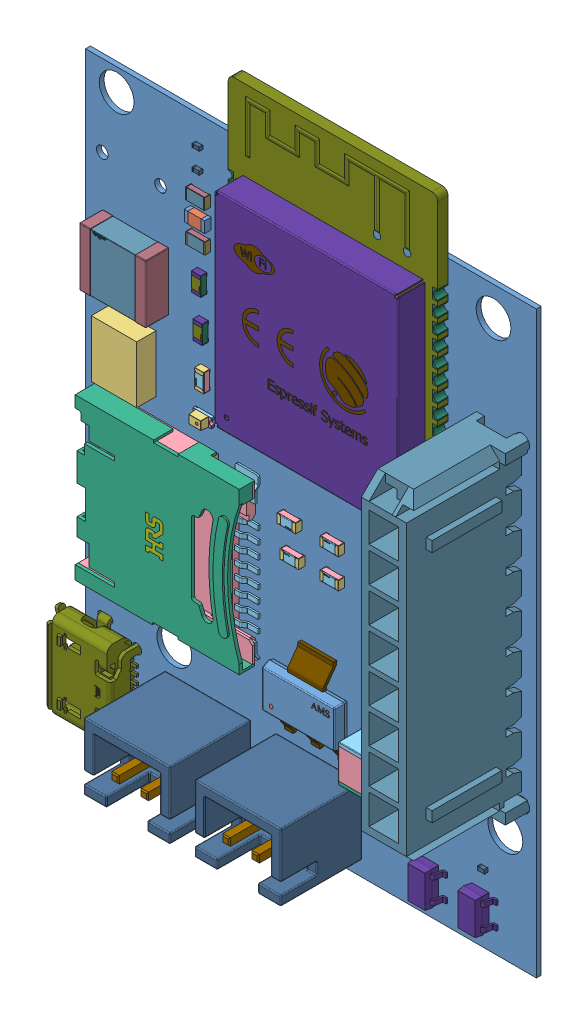
SolidWorks assembly PCB1.step, configuration Default. Lengths in mm.
Overall size (39.59 54.93 13.33).
223 component instances, 63 part files, 0 mates.
Components (placement in the parent):
- Board.step-1: Board.step [Default] at origin size (38.73 49.78 0.41)
  - Open CASCADE STEP translator 7.5 1.1.1.step-1: Open CASCADE STEP translator 7.5 1.1.1.step [Default] at (0 0 -0.4115) size (38.73 49.78 0.41)
- D100.step-1: D100.step [Default] at origin size (1.6 0.8 0.9)
  - Diode_Lite-On_LTST-C190GKT_eec.step-1: Diode_Lite-On_LTST-C190GKT_eec.step [Default] at (150.229 50.673 0) x (-1 0 0) z (0 0 1) size (1.6 0.8 0.9)
    - 1.step-1: 1.step [Default] at (-0.1749 0.0038 0.001) size (0.2 0.2 0.05)
    - 2.step-1: 2.step [Default] at origin size (1.1 0.8 0.64)
    - 3.step-1: 3.step [Default] at origin size (1.6 0.8 0.28)
    - 4.step-1: 4.step [Default] at origin size (1.6 0.8 0.24)
    - Lite-On Logo Adjustable.step-1: Lite-On Logo Adjustable.step [Default] at (-0.9132 -0.3001 -1.9175) x (1 0 0) z (0 -1 0) size (0.21 0.05 0.1)
    - 5.step-1: 5.step [Default] at origin size (1.6 0.7 0.24)
    - 6.step-1: 6.step [Default] at origin size (1.6 0.15 0.24)
- J202.step-1: J202.step [Default] at origin size (7.4 5.75 10.4)
  - Conn_JST_B2B-XH-A_LF_SN_eec.step-1: Conn_JST_B2B-XH-A_LF_SN_eec.step [Default] at (160.02 27.305 0) x (-1 0 0) z (0 0 1) size (7.4 5.75 10.4)
    - 1-0.step-1: 1-0.step [Default] at (0 0.025 0) x (-1 0 0) z (0 1 0) size (7.4 10.4 5.75)
      - 1-1.step-1: 1-1.step [Default] at origin size (3.14 10.2 0.64)
      - B2B-XH-A.step-1: B2B-XH-A.step [Default] at origin size (7.4 7 5.75)
      - JST Logo adjustable.step-1: JST Logo adjustable.step [Default] at (-1.7267 5.5034 2.841) size (0.85 2.3 0.01)
- R103.step-1: R103.step [Default] at origin size (1.65 0.95 0.5)
  - 6292486080.step-1: 6292486080.step [Default] at (149.875 63.627 0) x (1 0 0) z (0 0 1) size (1.65 0.95 0.5)
    - Terminal.step-1: Terminal.step [Default] at (-0.825 -0.475 0) size (0.1 0.95 0.5)
      - Open CASCADE STEP translator 6.8 3.2.1.step-1: Open CASCADE STEP translator 6.8 3.2.1.step [Default] at origin size (0.1 0.95 0.5)
    - Terminal.step-2: Terminal.step [Default] at (0.825 0.475 0) x (-1 0 0) z (0 0 1) size (0.1 0.95 0.5)
      - Open CASCADE STEP translator 6.8 3.2.1.step-1: Open CASCADE STEP translator 6.8 3.2.1.step [Default] at origin size (0.1 0.95 0.5)
    - Mid_Body.step-1: Mid_Body.step [Default] at (-0.825 -0.475 0) size (1.55 0.95 0.4)
    - Mark.step-1: Mark.step [Default] at (-0.725 -0.475 0.45) size (1.45 0.95 0.05)
- R300.step-1: R300.step [Default] at origin size (1.6 0.8 0.56)
  - Res_Panasonic_Electronic_Components_ERA-3ARB202V_eec.step-1: Res_Panasonic_Electronic_Components_ERA-3ARB202V_eec.step [Default] at (165.9526 38.227 -0.4115) x (1 0 0) z (0 0 -1) size (1.6 0.8 0.56)
    - 1-2.step-1: 1-2.step [Default] at origin size (1.52 0.8 0.47)
    - 2-3.step-1: 2-3.step [Default] at origin size (1.08 0.8 0.04)
    - 3-4.step-1: 3-4.step [Default] at origin size (1.6 0.8 0.55)
    - Panasonic Logo.step-1: Panasonic Logo.step [Default] at (-0.1032 0.2046 0.451) size (0.41 0.06 0.11)
- R112.step-1: R112.step [Default] at origin size (1.75 0.95 0.55)
  - 6724292592.step-1: 6724292592.step [Default] at (149.135 65.278 0) size (0.3 0.95 0.55)
    - Extruded.step-1: Extruded.step [Default] at origin size (0.3 0.95 0.55)
  - 6724292592.step-2: 6724292592.step [Default] at (150.585 65.278 0) size (0.3 0.95 0.55)
    - Extruded.step-1: Extruded.step [Default] at origin size (0.3 0.95 0.55)
  - 6724292352.step-1: 6724292352.step [Default] at (149.86 65.278 0) size (1.15 0.95 0.55)
    - Extruded-5.step-1: Extruded-5.step [Default] at origin size (1.15 0.95 0.55)
- R111.step-1: R111.step [Default] at origin size (0.8 1.6 0.56)
  - Res_Panasonic_Electronic_Components_ERA-3ARB202V_eec.step-1: Res_Panasonic_Electronic_Components_ERA-3ARB202V_eec.step [Default] at (150.114 57.15 0) x (0 -1 0) z (0 0 1) size (1.6 0.8 0.56)
    - 1-2.step-1: 1-2.step [Default] at origin size (1.52 0.8 0.47)
    - 2-3.step-1: 2-3.step [Default] at origin size (1.08 0.8 0.04)
    - 3-4.step-1: 3-4.step [Default] at origin size (1.6 0.8 0.55)
    - Panasonic Logo.step-1: Panasonic Logo.step [Default] at (-0.1032 0.2046 0.451) size (0.41 0.06 0.11)
- R110.step-1: R110.step [Default] at origin size (0.8 1.6 0.56)
  - Res_Panasonic_Electronic_Components_ERA-3ARB202V_eec.step-1: Res_Panasonic_Electronic_Components_ERA-3ARB202V_eec.step [Default] at (149.987 60.6696 0) x (0 -1 0) z (0 0 1) size (1.6 0.8 0.56)
    - 1-2.step-1: 1-2.step [Default] at origin size (1.52 0.8 0.47)
    - 2-3.step-1: 2-3.step [Default] at origin size (1.08 0.8 0.04)
    - 3-4.step-1: 3-4.step [Default] at origin size (1.6 0.8 0.55)
    - Panasonic Logo.step-1: Panasonic Logo.step [Default] at (-0.1032 0.2046 0.451) size (0.41 0.06 0.11)
- R109.step-1: R109.step [Default] at origin size (1.6 0.8 0.56)
  - Res_Panasonic_ERJ-3GEYJ102V_eec.step-1: Res_Panasonic_ERJ-3GEYJ102V_eec.step [Default] at (157.988 44.196 0) x (1 0 0) z (0 0 1) size (1.6 0.8 0.56)
    - Pieza60.step-1: Pieza60.step [Default] at origin size (1.6 0.8 0.54)
    - Pieza63.step-1: Pieza63.step [Default] at (-0.65 -0.4 0.26) x (1 0 0) z (0 -1 0) size (1.5 0.44 0.8)
    - Pieza64.step-1: Pieza64.step [Default] at (0 -0.4 0.26) x (1 0 0) z (0 -1 0) size (1 0.06 0.8)
    - Pieza65.step-1: Pieza65.step [Default] at (-0.5 -0.4 0.55) x (-1 0 0) z (0 0 1) size (0.55 0.09 0.02)
- R108.step-1: R108.step [Default] at origin size (0.8 1.6 0.56)
  - Res_Panasonic_ERJ-3GEYJ102V_eec.step-1: Res_Panasonic_ERJ-3GEYJ102V_eec.step [Default] at (150.241 53.6051 0) x (0 1 0) z (0 0 1) size (1.6 0.8 0.56)
    - Pieza60.step-1: Pieza60.step [Default] at origin size (1.6 0.8 0.54)
    - Pieza63.step-1: Pieza63.step [Default] at (-0.65 -0.4 0.26) x (1 0 0) z (0 -1 0) size (1.5 0.44 0.8)
    - Pieza64.step-1: Pieza64.step [Default] at (0 -0.4 0.26) x (1 0 0) z (0 -1 0) size (1 0.06 0.8)
    - Pieza65.step-1: Pieza65.step [Default] at (-0.5 -0.4 0.55) x (-1 0 0) z (0 0 1) size (0.55 0.09 0.02)
- R107.step-1: R107.step [Default] at origin size (1.6 0.8 0.56)
  - Res_Panasonic_ERJ-3GEYJ102V_eec.step-1: Res_Panasonic_ERJ-3GEYJ102V_eec.step [Default] at (161.417 44.323 0) x (1 0 0) z (0 0 1) size (1.6 0.8 0.56)
    - Pieza60.step-1: Pieza60.step [Default] at origin size (1.6 0.8 0.54)
    - Pieza63.step-1: Pieza63.step [Default] at (-0.65 -0.4 0.26) x (1 0 0) z (0 -1 0) size (1.5 0.44 0.8)
    - Pieza64.step-1: Pieza64.step [Default] at (0 -0.4 0.26) x (1 0 0) z (0 -1 0) size (1 0.06 0.8)
    - Pieza65.step-1: Pieza65.step [Default] at (-0.5 -0.4 0.55) x (-1 0 0) z (0 0 1) size (0.55 0.09 0.02)
- R106.step-1: R106.step [Default] at origin size (1.6 0.8 0.56)
  - Res_Panasonic_ERJ-3GEYJ102V_eec.step-1: Res_Panasonic_ERJ-3GEYJ102V_eec.step [Default] at (161.417 46.863 0) x (1 0 0) z (0 0 1) size (1.6 0.8 0.56)
    - Pieza60.step-1: Pieza60.step [Default] at origin size (1.6 0.8 0.54)
    - Pieza63.step-1: Pieza63.step [Default] at (-0.65 -0.4 0.26) x (1 0 0) z (0 -1 0) size (1.5 0.44 0.8)
    - Pieza64.step-1: Pieza64.step [Default] at (0 -0.4 0.26) x (1 0 0) z (0 -1 0) size (1 0.06 0.8)
    - Pieza65.step-1: Pieza65.step [Default] at (-0.5 -0.4 0.55) x (-1 0 0) z (0 0 1) size (0.55 0.09 0.02)
- R105.step-1: R105.step [Default] at origin size (1.6 0.8 0.56)
  - Res_Panasonic_ERJ-3GEYJ102V_eec.step-1: Res_Panasonic_ERJ-3GEYJ102V_eec.step [Default] at (157.734 46.736 0) x (-1 0 0) z (0 0 1) size (1.6 0.8 0.56)
    - Pieza60.step-1: Pieza60.step [Default] at origin size (1.6 0.8 0.54)
    - Pieza63.step-1: Pieza63.step [Default] at (-0.65 -0.4 0.26) x (1 0 0) z (0 -1 0) size (1.5 0.44 0.8)
    - Pieza64.step-1: Pieza64.step [Default] at (0 -0.4 0.26) x (1 0 0) z (0 -1 0) size (1 0.06 0.8)
    - Pieza65.step-1: Pieza65.step [Default] at (-0.5 -0.4 0.55) x (-1 0 0) z (0 0 1) size (0.55 0.09 0.02)
- R104.step-1: R104.step [Default] at origin size (1.65 0.95 0.5)
  - 6292486080.step-1: 6292486080.step [Default] at (149.845 66.929 0) x (1 0 0) z (0 0 1) size (1.65 0.95 0.5)
    - Terminal.step-1: Terminal.step [Default] at (-0.825 -0.475 0) size (0.1 0.95 0.5)
      - Open CASCADE STEP translator 6.8 3.2.1.step-1: Open CASCADE STEP translator 6.8 3.2.1.step [Default] at origin size (0.1 0.95 0.5)
    - Terminal.step-2: Terminal.step [Default] at (0.825 0.475 0) x (-1 0 0) z (0 0 1) size (0.1 0.95 0.5)
      - Open CASCADE STEP translator 6.8 3.2.1.step-1: Open CASCADE STEP translator 6.8 3.2.1.step [Default] at origin size (0.1 0.95 0.5)
    - Mid_Body.step-1: Mid_Body.step [Default] at (-0.825 -0.475 0) size (1.55 0.95 0.4)
    - Mark.step-1: Mark.step [Default] at (-0.725 -0.475 0.45) size (1.45 0.95 0.05)
- R100.step-1: R100.step [Default] at origin size (1.65 0.95 0.5)
  - 6606196528.step-1: 6606196528.step [Default] at (169.784 48.641 0) x (-1 0 0) z (0 0 1) size (1.65 0.95 0.5)
    - Terminal-1.step-1: Terminal-1.step [Default] at (-0.825 -0.475 0) size (0.1 0.95 0.5)
      - Open CASCADE STEP translator 6.8 3.2.1-6.step-1: Open CASCADE STEP translator 6.8 3.2.1-6.step [Default] at origin size (0.1 0.95 0.5)
    - Terminal-1.step-2: Terminal-1.step [Default] at (0.825 0.475 0) x (-1 0 0) z (0 0 1) size (0.1 0.95 0.5)
      - Open CASCADE STEP translator 6.8 3.2.1-6.step-1: Open CASCADE STEP translator 6.8 3.2.1-6.step [Default] at origin size (0.1 0.95 0.5)
    - Mid_Body-7.step-1: Mid_Body-7.step [Default] at (-0.825 -0.475 0) size (1.55 0.95 0.4)
    - Mark-8.step-1: Mark-8.step [Default] at (-0.725 -0.475 0.45) size (1.45 0.95 0.05)
- C302.step-1: C302.step [Default] at origin size (0.6 0.32 0.32)
  - Cap_Murata_GRM155R71C104KA88D_eec.step-1: Cap_Murata_GRM155R71C104KA88D_eec.step [Default] at (159.62 38.354 -0.4115) x (-1 0 0) z (0 0 -1) size (0.6 0.32 0.32)
- C301.step-1: C301.step [Default] at origin size (0.32 0.6 0.32)
  - Cap_Murata_GRM155R71C104KA88D_eec.step-1: Cap_Murata_GRM155R71C104KA88D_eec.step [Default] at (169.037 38.354 -0.4115) x (0 -1 0) z (0 0 -1) size (0.6 0.32 0.32)
- C300.step-1: C300.step [Default] at origin size (1.77 1.01 0.91)
  - 6724289712.step-1: 6724289712.step [Default] at (162.433 38.227 -1.3215) size (1.27 1.01 0.91)
    - Extruded-9.step-1: Extruded-9.step [Default] at origin size (1.27 1.01 0.91)
  - 6724289552.step-1: 6724289552.step [Default] at (161.673 38.227 -1.3215) size (0.25 1.01 0.91)
    - Extruded-10.step-1: Extruded-10.step [Default] at origin size (0.25 1.01 0.91)
  - 6724289552.step-2: 6724289552.step [Default] at (163.193 38.227 -1.3215) size (0.25 1.01 0.91)
    - Extruded-10.step-1: Extruded-10.step [Default] at origin size (0.25 1.01 0.91)
- C103.step-1: C103.step [Default] at origin size (0.6 0.32 0.32)
  - Cap_Murata_GRM155R71C104KA88D_eec.step-1: Cap_Murata_GRM155R71C104KA88D_eec.step [Default] at (149.733 68.834 0) x (1 0 0) z (0 0 1) size (0.6 0.32 0.32)
- C102.step-1: C102.step [Default] at origin size (5.7 5 2)
  - Cap_Murata_GRM55D7U2H333JW31K_eec.step-1: Cap_Murata_GRM55D7U2H333JW31K_eec.step [Default] at (144.272 59.182 0) x (-1 0 0) z (0 0 1) size (5.7 5 2)
    - Terminals.step-1: Terminals.step [Default] at origin size (5.7 5 2)
    - Center.step-1: Center.step [Default] at origin size (3.85 4.95 1.95)
    - Murata.step-1: Murata.step [Default] at origin size (1.17 0.26 0)
- C101.step-1: C101.step [Default] at origin size (0.6 0.32 0.32)
  - Cap_Murata_GRM155R71C104KA88D_eec.step-1: Cap_Murata_GRM155R71C104KA88D_eec.step [Default] at (149.733 70.612 0) x (1 0 0) z (0 0 1) size (0.6 0.32 0.32)
- J201.step-1: J201.step [Default] at origin size (5.4 8.2 3.3)
  - 1050170001.step-1: 1050170001.step [Default] at (141.8522 27.9402 1.1978) x (0 -1 0) z (-1 0 0) size (8.2 3.3 5.4)
    - Open CASCADE STEP translator 7.5 1.22.1.1.step-1: Open CASCADE STEP translator 7.5 1.22.1.1.step [Default] at origin size (8.2 3.3 5.4)
    - Open CASCADE STEP translator 7.5 1.22.1.2.step-1: Open CASCADE STEP translator 7.5 1.22.1.2.step [Default] at origin
- J200.step-1: J200.step [Default] at origin size (7.4 5.75 10.4)
  - Conn_JST_B2B-XH-A_LF_SN_eec.step-1: Conn_JST_B2B-XH-A_LF_SN_eec.step [Default] at (150.495 27.178 0) x (-1 0 0) z (0 0 1) size (7.4 5.75 10.4)
    - 1-0.step-1: 1-0.step [Default] at (0 0.025 0) x (-1 0 0) z (0 1 0) size (7.4 10.4 5.75)
      - 1-1.step-1: 1-1.step [Default] at origin size (3.14 10.2 0.64)
      - B2B-XH-A.step-1: B2B-XH-A.step [Default] at origin size (7.4 7 5.75)
      - JST Logo adjustable.step-1: JST Logo adjustable.step [Default] at (-1.7267 5.5034 2.841) size (0.85 2.3 0.01)
- U202.step-1: U202.step [Default] at origin size (2.8 2.9 1.3)
  - 6606193888.step-1: 6606193888.step [Default] at (169.672 26.035 0) x (-1 0 0) z (0 1 0) size (2.8 1.3 2.9)
- U201.step-1: U201.step [Default] at origin size (6.51 7.05 1.8)
  - IC_Advanced_Monolithic_Systems_AMS1117-3_3_eec.step-1: IC_Advanced_Monolithic_Systems_AMS1117-3_3_eec.step [Default] at (160.02 34.671 0) x (0 1 0) z (0 0 1) size (7.05 6.51 1.8)
    - 2-11.step-1: 2-11.step [Default] x (1 0 0) z (0 -1 0) size (7.05 1.2 5.34)
      - Open CASCADE STEP translator 7.5 1.25.1.2.1.step-1: Open CASCADE STEP translator 7.5 1.25.1.2.1.step [Default] at origin size (7.05 1.2 5.34)
      - Open CASCADE STEP translator 7.5 1.25.1.2.2.step-1: Open CASCADE STEP translator 7.5 1.25.1.2.2.step [Default] at origin
    - 1-12.step-1: 1-12.step [Default] at (0 0 0.74) x (0 1 0) z (0 0 1) size (6.51 3.5 1.06)
    - Notch 2.step-1: Notch 2.step [Default] at (-0.7251 1.7063 1.701) size (2.3 5.16 0.1)
- U200.step-1: U200.step [Default] at origin size (2.8 2.9 1.3)
  - 6606193888.step-1: 6606193888.step [Default] at (173.99 26.162 0) x (-1 0 0) z (0 1 0) size (2.8 1.3 2.9)
- U100.step-1: U100.step [Default] at origin size (3.9 4.9 1.65)
  - 6724294752.step-1: 6724294752.step [Default] at (144.145 52.578 0.1) size (3.9 4.9 1.65)
    - Extruded-13.step-1: Extruded-13.step [Default] at origin size (3.9 4.9 1.65)
- SD100.step-1: SD100.step [Default] at origin size (14.1 13.8 2.13)
  - Conn_HIROSE_DM3CS-SF_eec.step-1: Conn_HIROSE_DM3CS-SF_eec.step [Default] at (148.082 41.783 0) x (0 1 0) z (0 0 1) size (13.8 14.1 2.13)
    - DM3CS-SF.step-1: DM3CS-SF.step [Default] at (-224.49 -126.3634 0.025) size (13.4 14.1 1.71)
    - Pieza12.step-1: Pieza12.step [Default] at (-4.9 -6.9139 0.4322) x (0 -1 0) z (-1 0 0) size (13.6 1.46 13.8)
    - Pieza13.step-1: Pieza13.step [Default] at (-7.2639 -7.4211 1.98) size (13.8 14.1 1.96)
    - Pieza14.step-1: Pieza14.step [Default] at (-0.3875 0.3409 1.98) size (2.92 1.53 0)
- R201.step-1: R201.step [Default] at origin size (3.25 1.65 0.7)
  - 6724291552.step-1: 6724291552.step [Default] at (169.926 37.973 0) size (2.25 1.65 0.7)
    - Extruded-14.step-1: Extruded-14.step [Default] at origin size (2.25 1.65 0.7)
  - 6724291392.step-1: 6724291392.step [Default] at (168.551 37.973 0) size (0.5 1.65 0.7)
    - Extruded-15.step-1: Extruded-15.step [Default] at origin size (0.5 1.65 0.7)
  - 6724291392.step-2: 6724291392.step [Default] at (171.301 37.973 0) size (0.5 1.65 0.7)
    - Extruded-15.step-1: Extruded-15.step [Default] at origin size (0.5 1.65 0.7)
- R200.step-1: R200.step [Default] at origin size (1.65 0.95 0.5)
  - 6606196528.step-1: 6606196528.step [Default] at (169.276 30.734 0) x (-1 0 0) z (0 0 1) size (1.65 0.95 0.5)
    - Terminal-1.step-1: Terminal-1.step [Default] at (-0.825 -0.475 0) size (0.1 0.95 0.5)
      - Open CASCADE STEP translator 6.8 3.2.1-6.step-1: Open CASCADE STEP translator 6.8 3.2.1-6.step [Default] at origin size (0.1 0.95 0.5)
    - Terminal-1.step-2: Terminal-1.step [Default] at (0.825 0.475 0) x (-1 0 0) z (0 0 1) size (0.1 0.95 0.5)
      - Open CASCADE STEP translator 6.8 3.2.1-6.step-1: Open CASCADE STEP translator 6.8 3.2.1-6.step [Default] at origin size (0.1 0.95 0.5)
    - Mid_Body-7.step-1: Mid_Body-7.step [Default] at (-0.825 -0.475 0) size (1.55 0.95 0.4)
    - Mark-8.step-1: Mark-8.step [Default] at (-0.725 -0.475 0.45) size (1.45 0.95 0.05)
- Q200.step-1: Q200.step [Default] at origin size (2.92 2.37 1.12)
  - 6606200608.step-1: 6606200608.step [Default] at (169.611 34.333 0) x (0 -1 0) z (0 0 1) size (2.37 2.92 1.12)
    - Body.step-1: Body.step [Default] at origin size (1.3 2.92 1.06)
    - PinsArrayL.step-1: PinsArrayL.step [Default] at origin size (0.54 2.33 0.61)
    - FilletPinR.step-1: FilletPinR.step [Default] at origin size (0.54 0.43 0.61)
- P100.step-1: P100.step [Default] at origin size (5.57 27.65 13.08)
  - 66200811122.step-1: 66200811122.step [Default] at (175.7691 48.9044 4.98) x (0 1 0) z (-1 0 0) size (27.65 13.08 5.57)
    - 6620xx11122_PIN.step-1: 6620xx11122_PIN.step [Default] at (-10.5 1.3806 0.255) x (-1 0 0) z (0 0 -1) size (0.64 10.1 0.9)
    - 6620xx11122_PIN.step-2: 6620xx11122_PIN.step [Default] at (-7.5 1.3806 0.255) size (0.64 10.1 0.9)
    - 6620xx11122_PIN.step-3: 6620xx11122_PIN.step [Default] at (-4.5 1.3806 0.255) x (-1 0 0) z (0 0 -1) size (0.64 10.1 0.9)
    - 6620xx11122_PIN.step-4: 6620xx11122_PIN.step [Default] at (-1.5 1.3806 0.255) size (0.64 10.1 0.9)
    - 6620xx11122_PIN.step-5: 6620xx11122_PIN.step [Default] at (1.5 1.3806 0.255) x (-1 0 0) z (0 0 -1) size (0.64 10.1 0.9)
    - 6620xx11122_PIN.step-6: 6620xx11122_PIN.step [Default] at (4.5 1.3806 0.255) size (0.64 10.1 0.9)
    - 6620xx11122_PIN.step-7: 6620xx11122_PIN.step [Default] at (7.5 1.3806 0.255) x (-1 0 0) z (0 0 -1) size (0.64 10.1 0.9)
    - 6620xx11122_PIN.step-8: 6620xx11122_PIN.step [Default] at (10.5 1.3806 0.255) size (0.64 10.1 0.9)
    - 66200811122-16.step-1: 66200811122-16.step [Default] at origin size (27.65 11 5.57)
- M100.step-1: M100.step [Default] at origin size (18 25.5 3.2)
  - UNK_Espressif_Systems_ESP32-WROOM-32_eec.step-1: UNK_Espressif_Systems_ESP32-WROOM-32_eec.step [Default] at (162.106 65.289 0) x (1 0 0) z (0 0 1) size (18 25.5 3.2)
    - 1-1-17.step-1: 1-1-17.step [Default] x (1 0 0) z (0 -1 0) size (18 3.2 25.5)
      - 2-18.step-1: 2-18.step [Default] at origin size (18 0.9 18.46)
      - 3-19.step-1: 3-19.step [Default] at origin size (18 0.95 25.5)
      - ESP32-WROOM-32D.step-1: ESP32-WROOM-32D.step [Default] at origin size (15.81 2.3 17.61)
      - Logo.step-1: Logo.step [Default] at (0.4143 -0.204 -1.2063) x (1 0 0) z (0 1 0) size (11.53 10.26 0.01)
      - 10.step-1: 10.step [Default] at (0 0.9 0) x (-1 0 0) z (0 1 0) size (3.23 0.64 0)
      - 11.step-1: 11.step [Default] at (0 0.9 0) x (-1 0 0) z (0 1 0) size (0.34 2.67 0)
- Cam300.step-1: Cam300.step [Default] at origin size (18.6 6.6 2.05)
  - 524352471.step-1: 524352471.step [Default] at (163.4141 41.4938 -0.4615) x (1 0 0) z (0 1 0) size (18.6 2.05 6.6)
    - Open CASCADE STEP translator 7.5 1.34.1.1.step-1: Open CASCADE STEP translator 7.5 1.34.1.1.step [Default] at origin size (18.6 2.05 6.6)
    - Open CASCADE STEP translator 7.5 1.34.1.2.step-1: Open CASCADE STEP translator 7.5 1.34.1.2.step [Default] at origin
- C207.step-1: C207.step [Default] at origin size (10.26 11.53 4.3)
  - Cap_Murata_GRM188R60J106KE47D_eec.step-1: Cap_Murata_GRM188R60J106KE47D_eec.step [Default] at (172.974 32.639 0) x (0 -1 0) z (0 0 1) size (11.53 10.26 4.3) (hidden)
    - Terminals.step-1: Terminals.step [Default] at origin size (5.7 5 2) (hidden)
    - Body.step-1: Body.step [Default] at origin size (1.3 2.92 1.06) (hidden)
    - Logo.step-1: Logo.step [Default] at (-0.2332 0.5956 0.9) size (11.53 10.26 0.01) (hidden)
- C206.step-1: C206.step [Default] at origin size (0.6 0.32 0.32)
  - Cap_Murata_GRM155R71C104KA88D_eec.step-1: Cap_Murata_GRM155R71C104KA88D_eec.step [Default] at (169.526 29.083 0) x (1 0 0) z (0 0 1) size (0.6 0.32 0.32)
- C205.step-1: C205.step [Default] at origin size (10.26 11.53 4.3)
  - Cap_Murata_GRM188R60J106KE47D_eec.step-1: Cap_Murata_GRM188R60J106KE47D_eec.step [Default] at (166.116 26.3289 0) x (0 1 0) z (0 0 1) size (11.53 10.26 4.3) (hidden)
    - Terminals.step-1: Terminals.step [Default] at origin size (5.7 5 2) (hidden)
    - Body.step-1: Body.step [Default] at origin size (1.3 2.92 1.06) (hidden)
    - Logo.step-1: Logo.step [Default] at (-0.2332 0.5956 0.9) size (11.53 10.26 0.01) (hidden)
- C204.step-1: C204.step [Default] at origin size (11.53 10.26 4.3)
  - Cap_Murata_GRM188R60J106KE47D_eec.step-1: Cap_Murata_GRM188R60J106KE47D_eec.step [Default] at (165.8221 42.164 0) x (1 0 0) z (0 0 1) size (11.53 10.26 4.3) (hidden)
    - Terminals.step-1: Terminals.step [Default] at origin size (5.7 5 2) (hidden)
    - Body.step-1: Body.step [Default] at origin size (1.3 2.92 1.06) (hidden)
    - Logo.step-1: Logo.step [Default] at (-0.2332 0.5956 0.9) size (11.53 10.26 0.01) (hidden)
- C203.step-1: C203.step [Default] at origin size (2.5 3.2 2.7)
  - Cap_Murata_GRM32ER60J107ME20L_eec.step-1: Cap_Murata_GRM32ER60J107ME20L_eec.step [Default] at (165.608 33.275 0) x (0 1 0) z (0 0 1) size (2.6 2.5 2.7)
  - Cap_Murata_GRM32ER60J107ME20L_eec-20.step-1: Cap_Murata_GRM32ER60J107ME20L_eec-20.step [Default] at (165.608 33.275 0) x (0 1 0) z (0 0 1) size (0.3 2.5 2.7)
  - Cap_Murata_GRM32ER60J107ME20L_eec-21.step-1: Cap_Murata_GRM32ER60J107ME20L_eec-21.step [Default] at (165.608 33.275 0) x (0 1 0) z (0 0 1) size (0.3 2.5 2.7)
- C202.step-1: C202.step [Default] at origin size (11.53 10.26 4.3)
  - Cap_Murata_GRM188R60J106KE47D_eec.step-1: Cap_Murata_GRM188R60J106KE47D_eec.step [Default] at (165.735 37.973 0) x (1 0 0) z (0 0 1) size (11.53 10.26 4.3)
    - Terminals.step-1: Terminals.step [Default] at origin size (5.7 5 2) (hidden)
    - Body.step-1: Body.step [Default] at origin size (1.3 2.92 1.06) (hidden)
    - Logo.step-1: Logo.step [Default] at (-0.2332 0.5956 0.9) size (11.53 10.26 0.01) (hidden)
- C201.step-1: C201.step [Default] at origin size (0.6 0.32 0.32)
  - Cap_Murata_GRM155R71C104KA88D_eec.step-1: Cap_Murata_GRM155R71C104KA88D_eec.step [Default] at (174.244 29.083 0) x (-1 0 0) z (0 0 1) size (0.6 0.32 0.32)
- C200.step-1: C200.step [Default] at origin size (10.26 11.53 4.3)
  - Cap_Murata_GRM188R60J106KE47D_eec.step-1: Cap_Murata_GRM188R60J106KE47D_eec.step [Default] at (176.784 26.4559 0) x (0 1 0) z (0 0 1) size (11.53 10.26 4.3)
    - Terminals.step-1: Terminals.step [Default] at origin size (5.7 5 2) (hidden)
    - Body.step-1: Body.step [Default] at origin size (1.3 2.92 1.06) (hidden)
    - Logo.step-1: Logo.step [Default] at (-0.2332 0.5956 0.9) size (11.53 10.26 0.01) (hidden)
